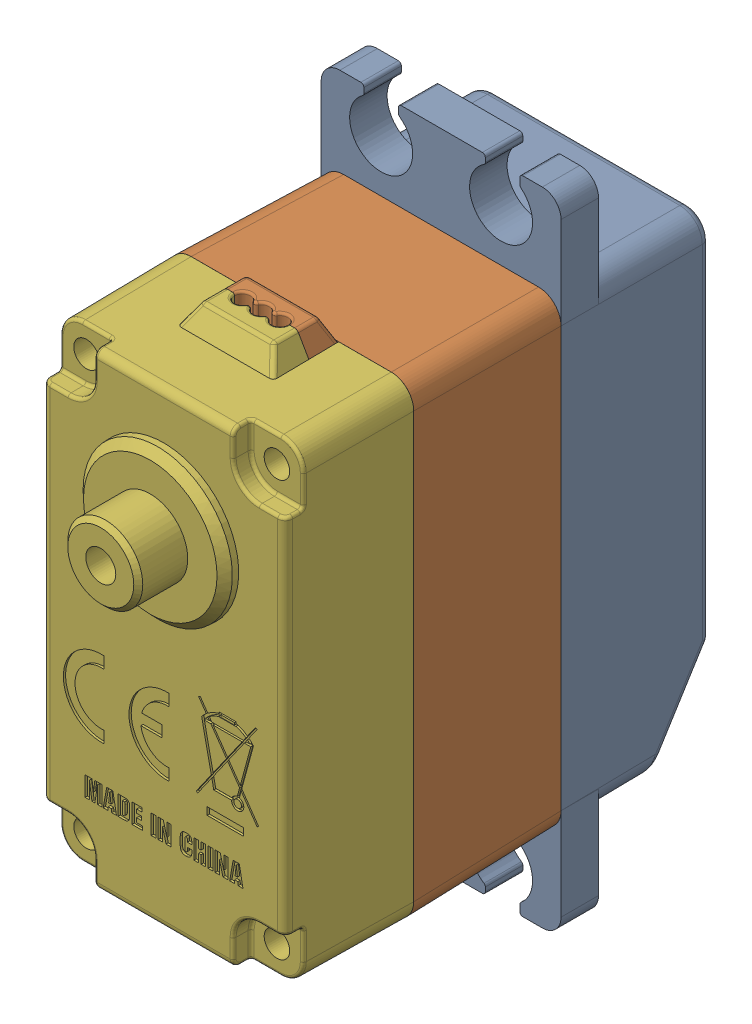
SolidWorks assembly 17G-SM-S3317M_ASM_11_ASM_2_ASM, configuration 默认. Lengths in mm.
Overall size (16.35 42.81 37.35).
4 component instances, 4 part files, 0 mates.
Components (placement in the parent):
- KE-01_9_1-1: KE-01_9_1 [默认] at origin size (16 42.81 11.52)
- KE-02_7_1-1: KE-02_7_1 [默认] at origin size (16.35 32.68 12.06)
- 04X33-05_3_1-1: 04X33-05_3_1 [默认] at (0 7.5 -3.05) size (4.97 4.97 4.58)
- 311-XK_8_1-1: 311-XK_8_1 [默认] at origin size (16.35 32.68 12.7)
